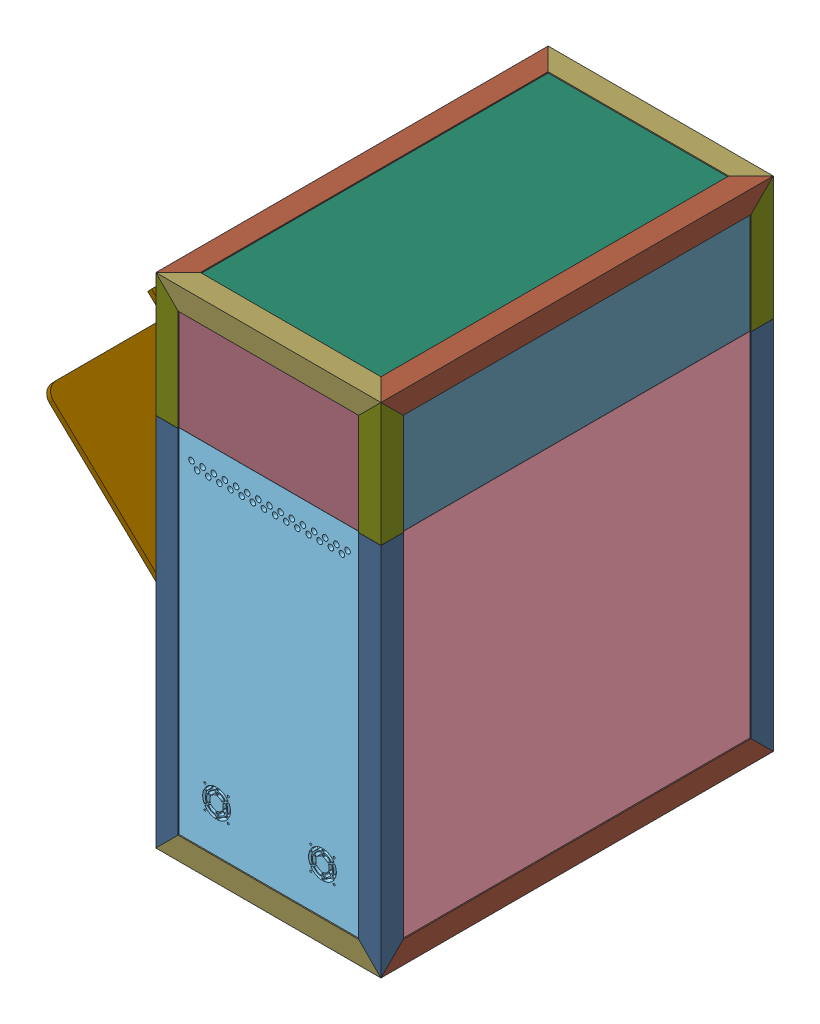
SolidWorks assembly carcasse, configuration Défaut. Lengths in mm.
Overall size (750.58 894.35 704).
58 component instances, 17 part files, 62 mates.
Components (placement in the parent):
- cadre_600x300mm-1: cadre_600x300mm [Défaut] at (-215.194 -19.8636 -400) size (380 40 680)
  - prof_40x40x600mm-1: prof_40x40x600mm [Défaut] at (-14.8937 4.0689 600) size (40 40 600)
  - Rexroth-Default-1: Rexroth-Default [Default] at (-14.8937 24.0689 720) x (0 -1 0) z (-1 0 0) size (40 40 40)
  - prof_40x40x600mm-3: prof_40x40x600mm [Défaut] at (325.1063 4.0689 600) size (40 40 600)
  - Rexroth-Default-3: Rexroth-Default [Default] at (-14.8937 24.0689 80) x (0 -1 0) z (0 0 -1) size (40 40 40)
  - Rexroth-Default-4: Rexroth-Default [Default] at (325.1063 24.0689 80) x (0 -1 0) z (1 0 0) size (40 40 40)
  - Rexroth-Default-5: Rexroth-Default [Default] at (325.1063 24.0689 720) x (0 -1 0) z (0 0 1) size (40 40 40)
  - prof_40x40x300mm-1: prof_40x40x300mm [Défaut] at (105.1063 4.0689 720) x (0 0 1) z (-1 0 0) size (40 40 300)
  - prof_40x40x300mm-2: prof_40x40x300mm [Défaut] at (105.1063 4.0689 80) x (0 0 1) z (-1 0 0) size (40 40 300)
- prof_40x40x600mm-1: prof_40x40x600mm [Défaut] at (109.9123 104.2053 -320) x (1 0 0) z (0 -1 0) size (40 40 600)
- prof_40x40x600mm-2: prof_40x40x600mm [Défaut] at (109.9123 104.2053 320) x (1 0 0) z (0 -1 0) size (40 40 600)
- prof_40x40x600mm-3: prof_40x40x600mm [Défaut] at (-230.0877 104.2053 320) x (1 0 0) z (0 -1 0) size (40 40 600)
- prof_40x40x600mm-4: prof_40x40x600mm [Défaut] at (-230.0877 104.2053 -320) x (1 0 0) z (0 -1 0) size (40 40 600)
- cadre_600x300mm-2: cadre_600x300mm [Défaut] at (95.0186 628.2742 -400) x (-1 0 0) z (0 0 1) size (380 40 680)
  - prof_40x40x600mm-1: prof_40x40x600mm [Défaut] at (-14.8937 4.0689 600) size (40 40 600)
  - Rexroth-Default-1: Rexroth-Default [Default] at (-14.8937 24.0689 720) x (0 -1 0) z (-1 0 0) size (40 40 40)
  - prof_40x40x600mm-3: prof_40x40x600mm [Défaut] at (325.1063 4.0689 600) size (40 40 600)
  - Rexroth-Default-3: Rexroth-Default [Default] at (-14.8937 24.0689 80) x (0 -1 0) z (0 0 -1) size (40 40 40)
  - Rexroth-Default-4: Rexroth-Default [Default] at (325.1063 24.0689 80) x (0 -1 0) z (1 0 0) size (40 40 40)
  - Rexroth-Default-5: Rexroth-Default [Default] at (325.1063 24.0689 720) x (0 -1 0) z (0 0 1) size (40 40 40)
  - prof_40x40x300mm-1: prof_40x40x300mm [Défaut] at (105.1063 4.0689 720) x (0 0 1) z (-1 0 0) size (40 40 300)
  - prof_40x40x300mm-2: prof_40x40x300mm [Défaut] at (105.1063 4.0689 80) x (0 0 1) z (-1 0 0) size (40 40 300)
- plaque_acrylique_680x670-2: plaque_acrylique_680x670 [Défaut] at (129.9123 299.2053 0) x (0 0 -1) z (1 0 0) size (680 670 10)
- plaque_acrylique_380x670-1: plaque_acrylique_380x670 [Défaut] at (-60.0877 299.2053 -350) size (380 670 10)
- plaque_acrylique_380x670-2: plaque_acrylique_380x670 [Défaut] at (-60.0877 299.2053 340) size (380 670 10)
- plaque_acrylique_680x670_porte-1: plaque_acrylique_680x670_porte [Défaut] at (-260.0877 299.2053 0) x (0 0 -1) z (1 0 0) size (680 670 10)
- charniere-1: charniere [Défaut] at (-253.7309 154.2053 256.2875) x (0 0 1) z (0 -1 0) size (40 29.08 53.23)
  - axe charnière-1: axe charnière [Défaut] at (-76.2875 9.8568 0) size (40 5 5)
  - batant charnière-1: batant charnière [Défaut] at (-76.2875 10.1991 -17.6196) size (40 7 33.5)
  - batant charnière-2: batant charnière [Défaut] at (-36.2875 -2.6626 12.4029) x (-1 0 0) z (0 0.723942 -0.689861) size (40 7 33.5)
- charniere-2: charniere [Défaut] at (-253.7309 154.2053 -143.7125) x (0 0 1) z (0 -1 0) size (40 29.08 53.23)
  - axe charnière-1: axe charnière [Défaut] at (-76.2875 9.8568 0) size (40 5 5)
  - batant charnière-1: batant charnière [Défaut] at (-76.2875 10.1991 -17.6196) size (40 7 33.5)
  - batant charnière-2: batant charnière [Défaut] at (-36.2875 -2.6626 12.4029) x (-1 0 0) z (0 0.723942 -0.689861) size (40 7 33.5)
- porte-1: porte [Défaut] at (-366.1448 256.769 0) x (0 0 -1) z (0.689861 0.723942 0) size (480 480 10)
- eclisse_40x40x670_bisote_x1-1: eclisse_40x40x670_bisote_x1 [Défaut] at (-242.0877 -37.7947 -331.8864) size (40 672 40)
- eclisse_40x40x670_bisote_x1-2: eclisse_40x40x670_bisote_x1 [Défaut] at (-241.9741 -37.7947 332) x (0 0 -1) z (1 0 0) size (40 672 40)
- eclisse_40x40x670_bisote_x1-3: eclisse_40x40x670_bisote_x1 [Défaut] at (121.9123 -37.7947 331.8864) x (-1 0 0) z (0 0 -1) size (40 672 40)
- eclisse_40x40x670_bisote_x1-4: eclisse_40x40x670_bisote_x1 [Défaut] at (121.7986 -37.7947 -332) x (0 0 1) z (-1 0 0) size (40 672 40)
- eclisse_40x40x704_bisote_x2-1: eclisse_40x40x704_bisote_x2 [Défaut] at (121.7986 -17.7947 352) x (0 1 0) z (-1 0 0) size (40 704 40)
- eclisse_40x40x704_bisote_x2-2: eclisse_40x40x704_bisote_x2 [Défaut] at (-242.0877 -17.681 352) x (1 0 0) z (0 1 0) size (40 704 40)
- eclisse_40x40x404_bisote_x2-1: eclisse_40x40x404_bisote_x2 [Défaut] at (141.9123 -17.681 332) x (0 0 -1) z (0 1 0) size (40 404 40)
- eclisse_40x40x404_bisote_x2-2: eclisse_40x40x404_bisote_x2 [Défaut] at (141.9123 -17.7947 -331.8864) x (0 1 0) z (0 0 1) size (40 404 40)
- couvercle-1: couvercle [Défaut] at (127.4119 748.2742 345) size (404 222 704)
  - plaque_acrylique_380x210-1: plaque_acrylique_380x210 [Défaut] at (-187.4996 -8.7215 -5) size (380 210 10)
  - plaque_acrylique_680x210-1: plaque_acrylique_680x210 [Défaut] at (2.5004 -8.7215 -345) x (0 0 -1) z (1 0 0) size (680 210 10)
  - plaque_acrylique_680x210-2: plaque_acrylique_680x210 [Défaut] at (-387.4996 -8.7215 -345) x (0 0 -1) z (1 0 0) size (680 210 10)
  - plaque_acrylique_380x210-2: plaque_acrylique_380x210 [Défaut] at (-187.4996 -8.7215 -695) size (380 210 10)
  - plaque_acrylique_380x680-1: plaque_acrylique_380x680 [Défaut] at (-187.4996 96.2785 -345) x (1 0 0) z (0 1 0) size (380 680 10)
  - eclisse_40x40x404_bisote_x2-1: eclisse_40x40x404_bisote_x2 [Défaut] at (14.5004 88.1649 -677) x (0 0 1) z (0 -1 0) size (40 404 40)
  - eclisse_40x40x704_bisote_x2-1: eclisse_40x40x704_bisote_x2 [Défaut] at (-5.6132 88.2785 -697) x (0 -1 0) z (-1 0 0) size (40 704 40)
  - eclisse_40x40x404_bisote_x2-2: eclisse_40x40x404_bisote_x2 [Défaut] at (-389.4996 88.1649 -13) x (0 0 -1) z (0 -1 0) size (40 404 40)
  - eclisse_40x40x704_bisote_x2-2: eclisse_40x40x704_bisote_x2 [Défaut] at (-369.4996 88.1649 -697) x (1 0 0) z (0 -1 0) size (40 704 40)
  - eclisse_40x40x222_bisote_x1-1: eclisse_40x40x222_bisote_x1 [Défaut] at (-369.386 108.2785 -677) x (0 0 1) z (1 0 0) size (40 222 40)
  - eclisse_40x40x222_bisote_x1-2: eclisse_40x40x222_bisote_x1 [Défaut] at (-5.4996 108.2785 -676.8864) x (-1 0 0) z (0 0 1) size (40 222 40)
  - eclisse_40x40x222_bisote_x1-3: eclisse_40x40x222_bisote_x1 [Défaut] at (-5.6132 108.2785 -13) x (0 0 -1) z (-1 0 0) size (40 222 40)
  - eclisse_40x40x222_bisote_x1-4: eclisse_40x40x222_bisote_x1 [Défaut] at (-369.4996 108.2785 -13.1136) x (1 0 0) z (0 0 -1) size (40 222 40)
- plaque_repartition_aire_chaud_300x544mm-1: plaque_repartition_aire_chaud_300x544mm [Défaut] at (-60.0936 129.2053 0) x (0 0 -1) z (1 0 0) size (680 10 324)
Mates (geometry in assembly coordinates):
- Coïncidente1: coincident anti-aligned: plane of cadre_600x300mm-1/Rexroth-Default-3 through (-230.0877 4.2053 -320) normal (0 1 0); plane of prof_40x40x600mm-4 through (-213.0877 4.2053 -337) normal (0 -1 0)
- Coïncidente2: coincident anti-aligned: plane of cadre_600x300mm-1/Rexroth-Default-1 through (-230.0877 4.2053 320) normal (0 1 0); plane of prof_40x40x600mm-3 through (-213.0877 4.2053 303) normal (0 -1 0)
- Coïncidente3: coincident anti-aligned: plane of cadre_600x300mm-1/Rexroth-Default-5 through (109.9123 4.2053 320) normal (0 1 0); plane of prof_40x40x600mm-2 through (126.9123 4.2053 303) normal (0 -1 0)
- Coïncidente4: coincident anti-aligned: plane of cadre_600x300mm-1/Rexroth-Default-4 through (109.9123 4.2053 -320) normal (0 1 0); plane of prof_40x40x600mm-1 through (126.9123 4.2053 -337) normal (0 -1 0)
- Coïncidente5: coincident aligned: plane of cadre_600x300mm-1/Rexroth-Default-4 through (129.9123 -15.7947 -320) normal (1 0 0); plane of prof_40x40x600mm-1 through (129.9123 604.2053 -314) normal (1 0 0)
- Coïncidente6: coincident aligned: plane of cadre_600x300mm-1/Rexroth-Default-4 through (109.9123 -15.7947 -340) normal (0 0 -1); plane of prof_40x40x600mm-1 through (115.9123 604.2053 -340) normal (0 0 -1)
- Coïncidente7: coincident aligned: plane of cadre_600x300mm-1/Rexroth-Default-5 through (129.9123 -15.7947 320) normal (1 0 0); plane of prof_40x40x600mm-2 through (129.9123 604.2053 303) normal (1 0 0)
- Coïncidente8: coincident aligned: plane of cadre_600x300mm-1/Rexroth-Default-5 through (109.9123 -15.7947 340) normal (0 0 1); plane of prof_40x40x600mm-2 through (126.9123 604.2053 340) normal (0 0 1)
- Coïncidente9: coincident aligned: plane of cadre_600x300mm-1/Rexroth-Default-1 through (-230.0877 -15.7947 340) normal (0 0 1); plane of prof_40x40x600mm-3 through (-213.0877 604.2053 340) normal (0 0 1)
- Coïncidente10: coincident aligned: plane of cadre_600x300mm-1/Rexroth-Default-1 through (-250.0877 -15.7947 320) normal (-1 0 0); plane of prof_40x40x600mm-3 through (-250.0877 604.2053 337) normal (-1 0 0)
- Coïncidente11: coincident aligned: plane of cadre_600x300mm-1/Rexroth-Default-3 through (-250.0877 -15.7947 -320) normal (-1 0 0); plane of prof_40x40x600mm-4 through (-250.0877 604.2053 -303) normal (-1 0 0)
- Coïncidente12: coincident aligned: plane of cadre_600x300mm-1/Rexroth-Default-3 through (-230.0877 -15.7947 -340) normal (0 0 -1); plane of prof_40x40x600mm-4 through (-247.0877 604.2053 -340) normal (0 0 -1)
- Coïncidente13: coincident anti-aligned: plane of prof_40x40x600mm-1 through (126.9123 604.2053 -337) normal (0 1 0); plane of cadre_600x300mm-2/Rexroth-Default-3 through (109.9123 604.2053 -320) normal (0 -1 0)
- Coïncidente14: coincident aligned: plane of prof_40x40x600mm-3 through (-250.0877 604.2053 337) normal (-1 0 0); plane of cadre_600x300mm-2/Rexroth-Default-5 through (-250.0877 624.2053 320) normal (-1 0 0)
- Coïncidente15: coincident aligned: plane of prof_40x40x600mm-3 through (-236.0877 604.2053 340) normal (0 0 1); plane of cadre_600x300mm-2/Rexroth-Default-5 through (-230.0877 624.2053 340) normal (0 0 1)
- Coïncidente38: coincident anti-aligned: plane of cadre_600x300mm-2/prof_40x40x600mm-1 through (129.9123 630.2053 -300) normal (1 0 0); plane of plaque_acrylique_680x670-2 through (129.9123 299.2053 0) normal (-1 0 0)
- Coïncidente39: coincident aligned: plane of prof_40x40x600mm-2 through (126.9123 604.2053 340) normal (0 0 1); plane of plaque_acrylique_680x670-2 through (139.9123 634.2053 340) normal (0 0 1)
- Coïncidente40: coincident aligned: plane of cadre_600x300mm-1/prof_40x40x600mm-3 through (115.9123 -35.7947 -300) normal (0 -1 0); plane of plaque_acrylique_680x670-2 through (139.9123 -35.7947 340) normal (0 -1 0)
- Coïncidente41: coincident anti-aligned: plane of prof_40x40x600mm-3 through (-213.0877 604.2053 340) normal (0 0 1); plane of plaque_acrylique_380x670-2 through (-60.0877 299.2053 340) normal (0 0 -1)
- Coïncidente42: coincident aligned: plane of cadre_600x300mm-2/Rexroth-Default-5 through (-250.0877 624.2053 320) normal (-1 0 0); plane of plaque_acrylique_380x670-2 through (-250.0877 634.2053 350) normal (-1 0 0)
- Coïncidente43: coincident aligned: plane of cadre_600x300mm-1/prof_40x40x300mm-1 through (89.9123 -35.7947 326) normal (0 -1 0); plane of plaque_acrylique_380x670-2 through (-250.0877 -35.7947 350) normal (0 -1 0)
- Coïncidente44: coincident aligned: plane of cadre_600x300mm-1/prof_40x40x300mm-2 through (89.9123 -35.7947 -337) normal (0 -1 0); plane of plaque_acrylique_380x670-1 through (-250.0877 -35.7947 -340) normal (0 -1 0)
- Coïncidente45: coincident aligned: plane of cadre_600x300mm-2/Rexroth-Default-4 through (-250.0877 624.2053 -320) normal (-1 0 0); plane of plaque_acrylique_380x670-1 through (-250.0877 634.2053 -340) normal (-1 0 0)
- Coïncidente46: coincident anti-aligned: plane of prof_40x40x600mm-4 through (-247.0877 604.2053 -340) normal (0 0 -1); plane of plaque_acrylique_380x670-1 through (-60.0877 299.2053 -340) normal (0 0 1)
- Coïncidente48: coincident aligned: plane of cadre_600x300mm-2/Rexroth-Default-5 through (-230.0877 624.2053 340) normal (0 0 1); plane of plaque_acrylique_680x670_porte-1 through (-250.0877 634.2053 340) normal (0 0 1)
- Coïncidente49: coincident aligned: plane of cadre_600x300mm-1/prof_40x40x600mm-1 through (-247.0877 -35.7947 -300) normal (0 -1 0); plane of plaque_acrylique_680x670_porte-1 through (-250.0877 -35.7947 340) normal (0 -1 0)
- Coïncidente50: coincident anti-aligned: plane of plaque_acrylique_680x670_porte-1 through (-260.0877 299.2053 0) normal (-1 0 0); plane of charniere-1/batant charnière-1 through (-260.0877 114.2053 220) normal (1 0 0)
- Coïncidente51: coincident anti-aligned: plane of plaque_acrylique_680x670_porte-1 through (-260.0877 299.2053 0) normal (-1 0 0); plane of charniere-2/batant charnière-1 through (-260.0877 114.2053 -180) normal (1 0 0)
- Distance4: distance = 20 mm anti-aligned: plane of charniere-2/batant charnière-1 through (-263.5877 154.2053 -220) normal (0 0 -1); plane of plaque_acrylique_680x670_porte-1 through (-260.0877 574.2053 -240) normal (0 0 1)
- Coïncidente54: coincident aligned: line of plaque_acrylique_680x670_porte-1 through (-260.0877 154.2053 220) axis (0 0 -1); line of charniere-2/batant charnière-1 through (-260.0877 154.2053 -180) axis (0 0 -1)
- Distance5: distance = 20 mm anti-aligned: plane of plaque_acrylique_680x670_porte-1 through (-260.0877 574.2053 240) normal (0 0 -1); plane of charniere-1/batant charnière-1 through (-263.5877 154.2053 220) normal (0 0 1)
- Coïncidente57: coincident aligned: line of plaque_acrylique_680x670_porte-1 through (-260.0877 154.2053 220) axis (0 0 -1); line of charniere-1/batant charnière-1 through (-260.0877 154.2053 220) axis (0 0 -1)
- Coïncidente62: coincident anti-aligned: plane of charniere-1/batant charnière-2 through (-290.1309 184.3336 180) normal (0.689861 0.723942 0); plane of porte-1 through (-586.947 467.1766 30) normal (-0.689861 -0.723942 0)
- Coïncidente63: coincident anti-aligned: line of charniere-1/batant charnière-2 through (-261.1732 156.7391 200) axis (0 0 1); line of porte-1 through (-261.1732 156.7391 220) axis (0 0 -1)
- Coïncidente64: coincident anti-aligned: plane of plaque_acrylique_680x670_porte-1 through (-260.0877 574.2053 240) normal (0 0 -1); plane of porte-1 through (-558.3301 453.7202 240) normal (0 0 1)
- Coïncidente65: coincident anti-aligned: plane of plaque_acrylique_380x670-1 through (-60.0877 299.2053 -350) normal (0 0 -1); plane of eclisse_40x40x670_bisote_x1-1 through (-260.0877 634.2053 -350) normal (0 0 1)
- Coïncidente66: coincident anti-aligned: plane of plaque_acrylique_680x670_porte-1 through (-260.0877 299.2053 0) normal (-1 0 0); plane of eclisse_40x40x670_bisote_x1-1 through (-260.0877 634.2053 -350) normal (1 0 0)
- Coïncidente67: coincident aligned: plane of plaque_acrylique_680x670_porte-1 through (-250.0877 634.2053 340) normal (0 1 0); plane of eclisse_40x40x670_bisote_x1-1 through (-242.0877 634.2053 -331.8864) normal (0 1 0)
- Coïncidente68: coincident anti-aligned: plane of plaque_acrylique_680x670-2 through (139.9123 299.2053 0) normal (1 0 0); plane of eclisse_40x40x670_bisote_x1-4 through (139.9123 634.2053 -350) normal (-1 0 0)
- Coïncidente69: coincident anti-aligned: plane of plaque_acrylique_380x670-1 through (-60.0877 299.2053 -350) normal (0 0 -1); plane of eclisse_40x40x670_bisote_x1-4 through (139.9123 634.2053 -350) normal (0 0 1)
- Coïncidente70: coincident aligned: plane of plaque_acrylique_380x670-1 through (-250.0877 634.2053 -340) normal (0 1 0); plane of eclisse_40x40x670_bisote_x1-4 through (121.7986 634.2053 -332) normal (0 1 0)
- Coïncidente71: coincident anti-aligned: plane of plaque_acrylique_380x670-2 through (-60.0877 299.2053 350) normal (0 0 1); plane of eclisse_40x40x670_bisote_x1-2 through (-260.0877 634.2053 350) normal (0 0 -1)
- Coïncidente72: coincident anti-aligned: plane of plaque_acrylique_680x670_porte-1 through (-260.0877 299.2053 0) normal (-1 0 0); plane of eclisse_40x40x670_bisote_x1-2 through (-260.0877 634.2053 350) normal (1 0 0)
- Coïncidente73: coincident aligned: plane of plaque_acrylique_380x670-2 through (-250.0877 634.2053 350) normal (0 1 0); plane of eclisse_40x40x670_bisote_x1-2 through (-241.9741 634.2053 332) normal (0 1 0)
- Coïncidente74: coincident anti-aligned: plane of plaque_acrylique_680x670-2 through (139.9123 299.2053 0) normal (1 0 0); plane of eclisse_40x40x670_bisote_x1-3 through (139.9123 634.2053 350) normal (-1 0 0)
- Coïncidente75: coincident anti-aligned: plane of plaque_acrylique_380x670-2 through (-60.0877 299.2053 350) normal (0 0 1); plane of eclisse_40x40x670_bisote_x1-3 through (139.9123 634.2053 350) normal (0 0 -1)
- Coïncidente76: coincident aligned: plane of plaque_acrylique_380x670-2 through (-250.0877 634.2053 350) normal (0 1 0); plane of eclisse_40x40x670_bisote_x1-3 through (121.9123 634.2053 331.8864) normal (0 1 0)
- Coïncidente77: coincident anti-aligned: plane of eclisse_40x40x670_bisote_x1-1 through (327.9123 -37.7947 -352) normal (0 -0.707107 0.707107); plane of eclisse_40x40x704_bisote_x2-2 through (-222.0877 -37.7947 -352) normal (0 0.707107 -0.707107)
- Coïncidente78: coincident aligned: plane of eclisse_40x40x670_bisote_x1-1 through (-262.0877 634.2053 -352) normal (-1 0 0); plane of eclisse_40x40x704_bisote_x2-2 through (-262.0877 -37.7947 -352) normal (-1 0 0)
- Coïncidente79: coincident anti-aligned: plane of eclisse_40x40x670_bisote_x1-2 through (327.9123 -37.7947 352) normal (0 -0.707107 -0.707107); plane of eclisse_40x40x704_bisote_x2-2 through (327.9123 -37.7947 352) normal (0 0.707107 0.707107)
- Coïncidente80: coincident anti-aligned: plane of eclisse_40x40x670_bisote_x1-4 through (-448.0877 -37.7947 -352) normal (0 -0.707107 0.707107); plane of eclisse_40x40x704_bisote_x2-1 through (101.9123 -37.7947 -352) normal (0 0.707107 -0.707107)
- Coïncidente81: coincident aligned: plane of eclisse_40x40x670_bisote_x1-4 through (141.9123 634.2053 -352) normal (1 0 0); plane of eclisse_40x40x704_bisote_x2-1 through (141.9123 -37.7947 -352) normal (1 0 0)
- Coïncidente82: coincident anti-aligned: plane of eclisse_40x40x670_bisote_x1-3 through (-448.0877 -37.7947 352) normal (0 -0.707107 -0.707107); plane of eclisse_40x40x704_bisote_x2-1 through (-448.0877 -37.7947 352) normal (0 0.707107 0.707107)
- Coïncidente86: coincident aligned: plane of eclisse_40x40x704_bisote_x2-1 through (141.9123 -37.7947 -352) normal (0 -1 0); plane of eclisse_40x40x404_bisote_x2-1 through (-262.0877 -37.7947 352) normal (0 -1 0)
- Coïncidente87: coincident aligned: plane of eclisse_40x40x670_bisote_x1-3 through (141.9123 634.2053 352) normal (0 0 1); plane of eclisse_40x40x404_bisote_x2-1 through (-262.0877 -37.7947 352) normal (0 0 1)
- Coïncidente88: coincident anti-aligned: plane of eclisse_40x40x670_bisote_x1-2 through (-262.0877 -37.7947 -238) normal (0.707107 -0.707107 0); plane of eclisse_40x40x404_bisote_x2-1 through (-262.0877 -37.7947 312) normal (-0.707107 0.707107 0)
- Coïncidente89: coincident aligned: plane of eclisse_40x40x670_bisote_x1-1 through (-262.0877 634.2053 -352) normal (0 0 -1); plane of eclisse_40x40x404_bisote_x2-2 through (-262.0877 -37.7947 -352) normal (0 0 -1)
- Coïncidente90: coincident aligned: plane of eclisse_40x40x704_bisote_x2-1 through (141.9123 -37.7947 -352) normal (0 -1 0); plane of eclisse_40x40x404_bisote_x2-2 through (-262.0877 -37.7947 -352) normal (0 -1 0)
- Coïncidente91: coincident anti-aligned: plane of eclisse_40x40x670_bisote_x1-1 through (-262.0877 -37.7947 238) normal (0.707107 -0.707107 0); plane of eclisse_40x40x404_bisote_x2-2 through (-262.0877 -37.7947 -312) normal (-0.707107 0.707107 0)
- Coïncidente92: coincident aligned: plane of eclisse_40x40x670_bisote_x1-1 through (-262.0877 634.2053 -352) normal (-1 0 0); plane of couvercle-1/eclisse_40x40x222_bisote_x1-1 through (-262.0877 634.5527 -352) normal (-1 0 0)
- Coïncidente93: coincident aligned: plane of eclisse_40x40x670_bisote_x1-1 through (-262.0877 634.2053 -352) normal (0 0 -1); plane of couvercle-1/eclisse_40x40x222_bisote_x1-1 through (-262.0877 634.5527 -352) normal (0 0 -1)
- Coïncidente100: coincident anti-aligned: plane of plaque_acrylique_380x670-2 through (-60.0877 299.2053 340) normal (0 0 -1); plane of plaque_repartition_aire_chaud_300x544mm-1 through (-210.0936 139.2053 340) normal (0 0 1)
